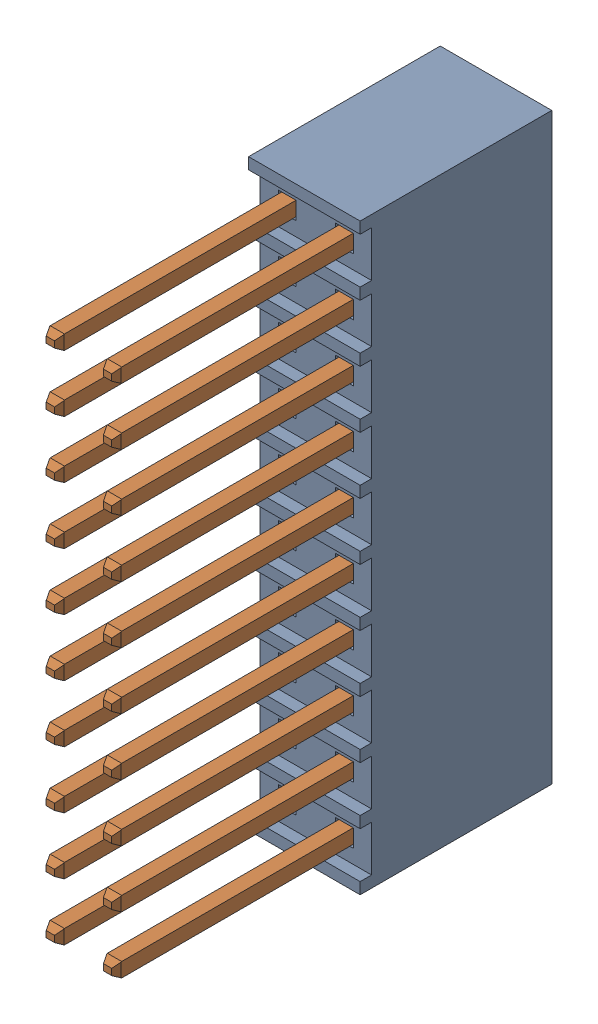
SolidWorks assembly J4, configuration Default. Lengths in mm.
Overall size (4.95 25.91 18.52).
3 component instances, 2 part files, 0 mates.
Components (placement in the parent):
- SSQ-110-03-T-D-1: SSQ-110-03-T-D [Default] at (49.5299 19.0499 -1.6154) x (0 -1 0) z (1 0 0) size (25.91 18.52 4.95)
  - SSQ-110-03-T-D_2-1: SSQ-110-03-T-D_2 [Default] at origin size (25.91 8.51 4.95)
  - SSQ-110-03-T-D_1-1: SSQ-110-03-T-D_1 [Default] at (0 -10.0076 0) size (23.9 11.02 3.76)
